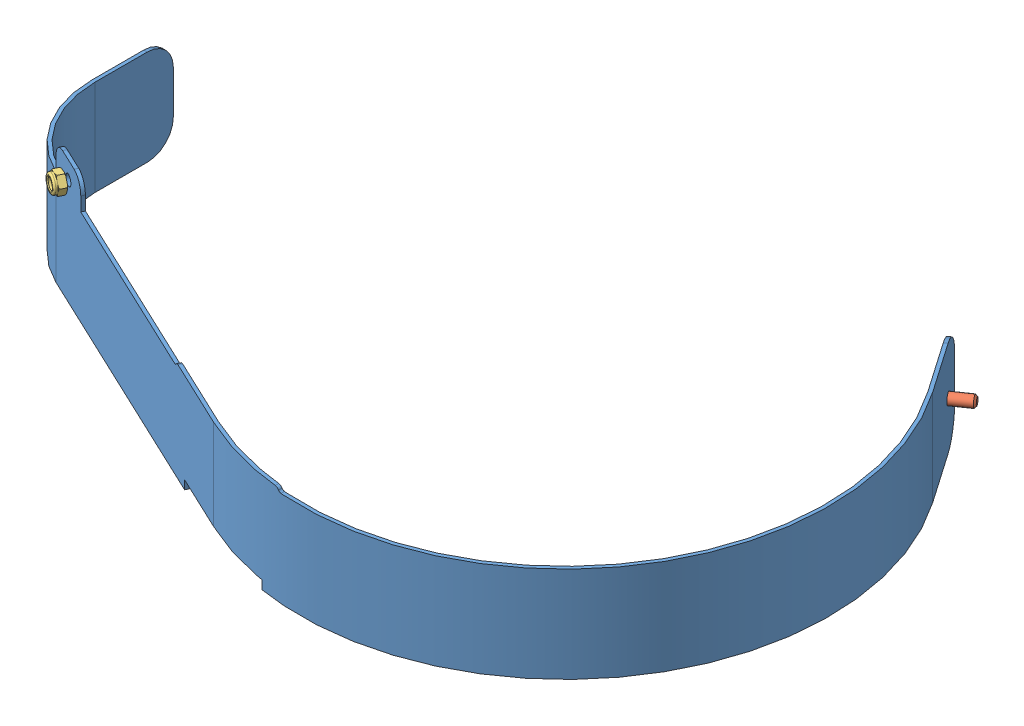
SolidWorks assembly PUTM-S-TR-GR-Chain_cover, configuration Domyślna. Lengths in mm.
Overall size (424.59 71 279.97).
3 component instances, 3 part files, 2 mates.
Components (placement in the parent):
- PUTM-S-TR-GR-Cover-1: PUTM-S-TR-GR-Cover [Domyślna] at (0 102.45 0) x (1 0 0) z (0 1 0) size (424.59 279.64 71)
- PUTM-FT-FABORY_DIN933-10: PUTM-FT-FABORY_DIN933 [M6x14 [01210.060.014]] at (-1471.6078 102.45 146.941) x (-0.822156 0 0.569262) z (-0.504986 -0.461599 -0.729325) size (18 11.55 10)
- PUTM-FT-FABORY_DIN985-6: PUTM-FT-FABORY_DIN985 [M6 [12348.060.001]] at (-1796.1685 135.95 323.2525) x (0.900042 0.094338 0.425471) z (-0.427377 0 0.904074) size (11.9 10.35 6.18)
Mates (geometry in assembly coordinates):
- Koncentryczne204: concentric anti-aligned: cylinder of PUTM-S-TR-GR-Cover-1 through (-1466.6749 102.45 143.5254) axis (-0.822156 0 0.569262) radius 3; cylinder of PUTM-FT-FABORY_DIN933-10 through (-1456.809 102.45 136.6943) axis (0.822156 0 -0.569262) radius 3
- Wspólnie176: coincident anti-aligned: plane of PUTM-S-TR-GR-Cover-1 through (-1448.395 129.95 173.4394) normal (-0.822156 0 0.569262); plane of PUTM-FT-FABORY_DIN933-10 through (-1469.633 106.8854 142.7664) normal (0.822156 0 -0.569262)
